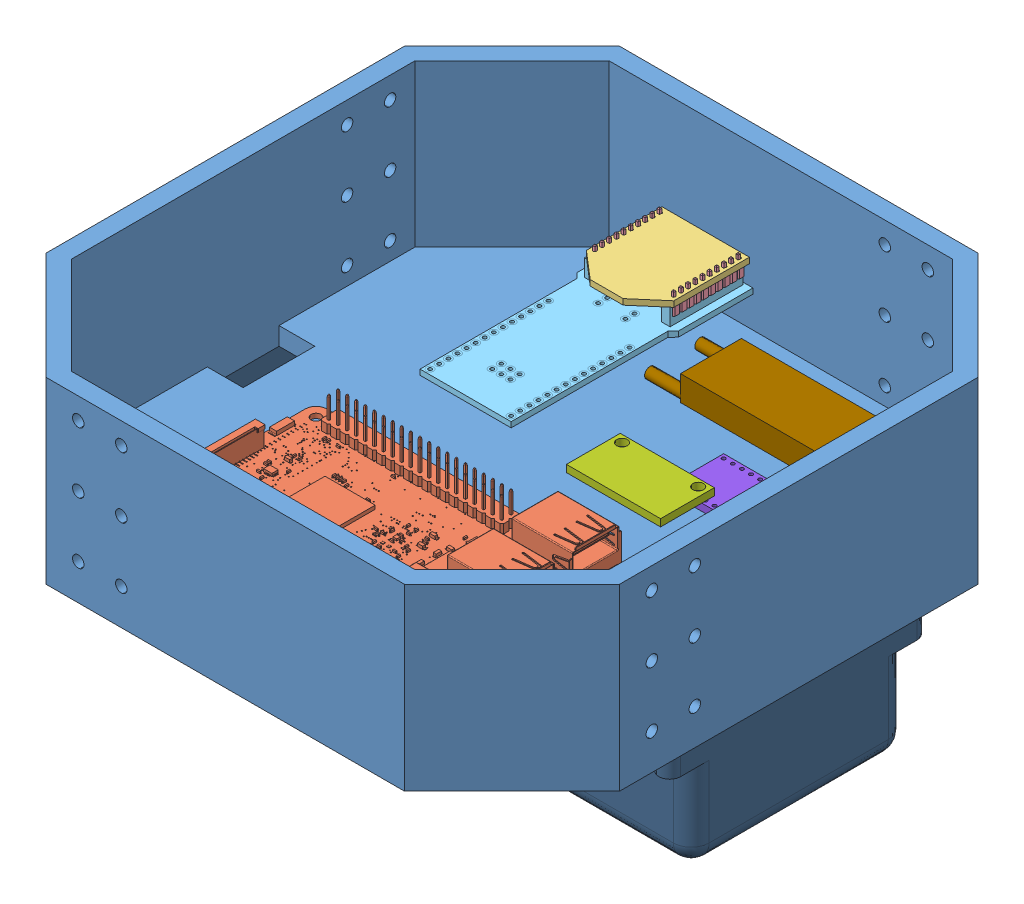
SolidWorks assembly _BodyElectronicAssembly, configuration Default. Lengths in mm.
Overall size (160 80 160).
13 component instances, 11 part files, 16 mates.
Components (placement in the parent):
- ElectronicHousing-1: ElectronicHousing [Default] at origin size (160 50 160)
- raspberryPi3B-1: raspberryPi3B [Detailed] at (-1.7687 10.6276 38.3991) x (1 0 0) z (0 1 0) size (87.05 58.5 19.5)
- XBee Module - ZB Series S2C - 2mW with Wire Antenna - XB24CZ7WIT-004-1: XBee Module - ZB Series S2C - 2mW with Wire Antenna - XB24CZ7WIT-004 [Default] at (-19.0662 24.0397 -73.0904) x (1 0 0) z (0 -1 0) size (24.38 27.61 11.07)
  - XBee Module - ZB Series S2C - 2mW with Wire Antenna - XB24CZ7WIT-004-1: XBee Module - ZB Series S2C - 2mW with Wire Antenna - XB24CZ7WIT-004 [Default] at origin size (24.38 27.61 1.59)
  - 2mm Header-1: 2mm Header [10] at (10.9932 19.9107 1.5875) size (2 20 11.07)
  - 2mm Header-2: 2mm Header [10] at (-11.0085 19.9063 1.5875) size (2 20 11.07)
- arduino_fio.stp-1: arduino_fio.stp [Default] at (-32.0499 17.7532 -72.4421) x (1 0 0) z (0 -1 0) size (28.25 66.04 8.74)
- batteryStandin-1: batteryStandin [Default] at (-61 -12 0) x (0 0 1) z (0 1 0) size (45 135 24)
- GY-9250-1: GY-9250 [Default] at (21.3864 13.63 -14.4322) size (26.25 2 15)
- I2C Logic Level Converter-1: I2C Logic Level Converter [Default] at (21.1364 6.155 -22.9188) size (15 2 15)
- BEC634717287951-1: BEC634717287951 [Default] at (3.1048 8.5 -43.8823) size (63 7 17)
- ElectronicHousingCover-1: ElectronicHousingCover [Default] at (0 50 0) x (1 0 0) z (0 1 0) size (160 160 5) (hidden)
- BatteryCageV2-1: BatteryCageV2 [Default] x (-1 0 0) z (0 -1 0) size (160 72 30)
Mates (geometry in assembly coordinates):
- Coincident1: coordinate: point of ElectronicHousing-1
- Coincident2: coincident anti-aligned: plane of XBee Module - ZB Series S2C - 2mW with Wire Antenna - XB24CZ7WIT-004-1/2mm Header-2 through (-29.7353 25.4494 -52.8446) normal (0 0 1); plane of arduino_fio.stp-1 through (-30.4142 22.4522 -52.8446) normal (0 0 -1)
- Coincident3: coincident anti-aligned: plane of XBee Module - ZB Series S2C - 2mW with Wire Antenna - XB24CZ7WIT-004-1/2mm Header-2 through (-30.4142 25.4494 -52.8446) normal (-1 0 0); plane of arduino_fio.stp-1 through (-30.4142 22.4522 -53.4796) normal (1 0 0)
- Coincident4: coincident anti-aligned: plane of XBee Module - ZB Series S2C - 2mW with Wire Antenna - XB24CZ7WIT-004-1/XBee Module - ZB Series S2C - 2mW with Wire Antenna - XB24CZ7WIT-004-1 through (-19.0662 22.4522 -73.0904) normal (0 -1 0); plane of arduino_fio.stp-1 through (-32.0499 22.4522 -72.4421) normal (0 1 0)
- InPlace1: in place: plane of ElectronicHousing-1 through (0 50 0) normal (0 1 0); plane of ElectronicHousingCover-1 through (0 50 0) normal (0 1 0); moOrthogonalPlaneRef_w of ElectronicHousing-1 through (0 50 0) normal (0 1 0); plane of ElectronicHousingCover-1 through (0 50 0) normal (0 0 -1); plane of ElectronicHousing-1 through (0 50 0) normal (0 1 0); plane of ElectronicHousingCover-1 through (0 50 0) normal (1 0 0); plane of ElectronicHousing-1 through (0 50 0) normal (0 1 0); unknown of ElectronicHousingCover-1
- Coincident5: coincident aligned: plane of ElectronicHousing-1; plane of ElectronicHousingCover-1
- Coincident6: coincident aligned: moOrthogonalPlaneRef_w of ElectronicHousing-1 through (0 50 0) normal (0 0 -1); plane of ElectronicHousingCover-1 through (0 50 0) normal (0 0 -1)
- Coincident7: coincident anti-aligned: moOrthogonalPlaneRef_w of ElectronicHousing-1 through (0 50 0) normal (-1 0 0); plane of ElectronicHousingCover-1 through (0 50 0) normal (1 0 0)
- Coincident8: coincident anti-aligned: plane of ElectronicHousing-1 through (0 0 0) normal (0 -1 0); plane of batteryStandin-1 through (74 0 -10.5) normal (0 1 0)
- Parallel1: parallel: line of batteryStandin-1 through (74 0 -10.5) axis (-1 0 0)
- Coincident11: coincident aligned: plane of batteryStandin-1 through (-61 -12 0) normal (0 0 1)
- Distance1: distance = 6 mm aligned: plane of ElectronicHousing-1 through (80 50 0) normal (1 0 0); plane of batteryStandin-1 through (74 -12 -10.5) normal (1 0 0)
- InPlace2: in place: plane of ElectronicHousing-1 through (0 0 0) normal (0 -1 0); plane of BatteryCageV2-1 through (0 0 0) normal (0 -1 0); plane of ElectronicHousing-1 through (0 0 0) normal (0 -1 0); plane of BatteryCageV2-1 through (0 0 0) normal (0 0 -1); plane of ElectronicHousing-1 through (0 0 0) normal (0 -1 0); plane of BatteryCageV2-1 through (0 0 0) normal (-1 0 0); plane of ElectronicHousing-1 through (0 0 0) normal (0 -1 0); unknown of BatteryCageV2-1
- Coincident13: coincident aligned: plane of ElectronicHousing-1; plane of BatteryCageV2-1
- Coincident14: coincident aligned: moOrthogonalPlaneRef_w of ElectronicHousing-1 through (0 0 0) normal (0 0 -1); plane of BatteryCageV2-1 through (0 0 0) normal (0 0 -1)
- Coincident15: coincident anti-aligned: moOrthogonalPlaneRef_w of ElectronicHousing-1 through (0 0 0) normal (1 0 0); plane of BatteryCageV2-1 through (0 0 0) normal (-1 0 0)
